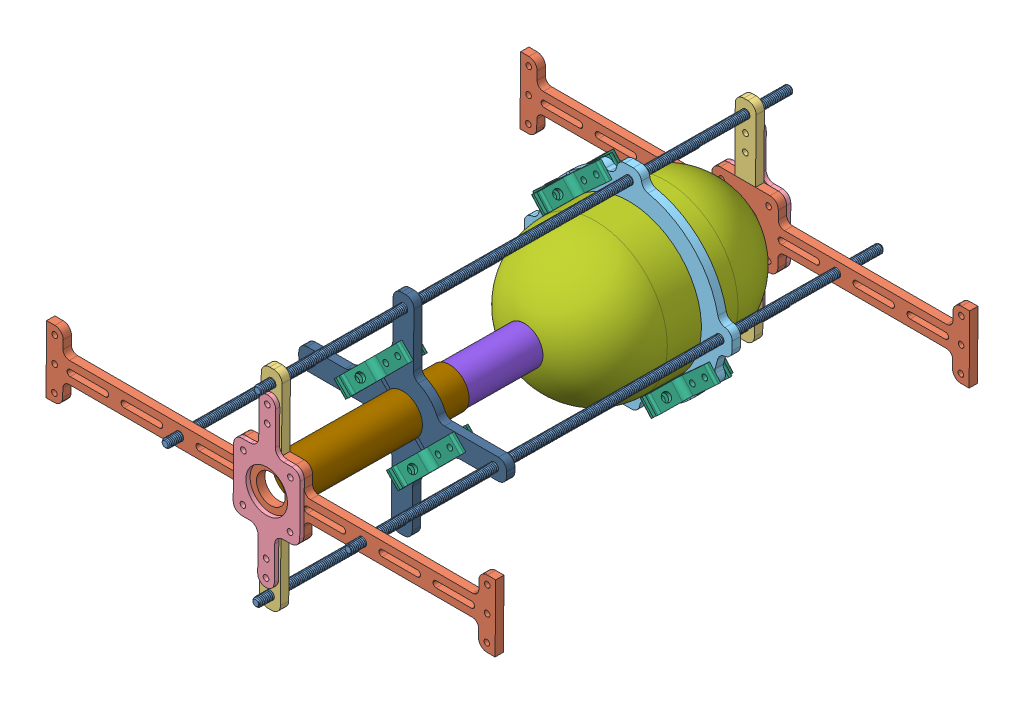
SolidWorks assembly FullCage, configuration Default. Lengths in mm.
Overall size (342.9 209.34 408.77).
42 component instances, 10 part files, 6 mates.
Components (placement in the parent):
- 98804A107_18-8 Stainless Steel Threaded Rod-1: 98804A107_18-8 Stainless Steel Threaded Rod [98804A107] at (0 -68.3672 170.2224) x (1 0 0) z (0 0.008727 0.999962) size (6.68 6.43 407.51)
- Cage Lid-1: Cage Lid [Default] x (1 0 0) z (0 -0.008727 -0.999962) size (342.9 158.75 9.53)
  - Bearing_CrossBarHeavy-1: Bearing_CrossBarHeavy [Default] at origin size (342.9 50.8 6.35)
  - CrossBar_Extension-1: CrossBar_Extension [Default] at (0 52.3875 0) x (0 -1 0) z (-1 0 0) size (53.98 6.35 15.88)
  - CrossBar_Extension-2: CrossBar_Extension [Default] at (0 -52.3875 0) x (0 1 0) z (1 0 0) size (53.98 6.35 15.88)
  - CageBracket-1: CageBracket [Default] at (0 0 9.525) x (0 1 0) z (-1 0 0) size (127 3.17 50.8)
- TankRing_Assy-1: TankRing_Assy [Default] at (0 0.7217 82.6939) x (0.73993 0.672659 -0.00587) z (0.672684 -0.739901 0.006457) size (180.05 57.15 180.38)
  - TankRing-1: TankRing [Default] x (0.73993 0 0.672684) z (-0.672684 0 0.73993) size (125.18 6.35 129.98)
  - TankRing_Bracket-1: TankRing_Bracket [8982K116] at (-17.4625 22.225 62.2074) size (31.75 25.4 12.7)
  - TankRing_Bracket-2: TankRing_Bracket [8982K116] at (-17.4625 22.225 -62.2074) size (31.75 25.4 12.7)
  - TankRing_Bracket-5: TankRing_Bracket [8982K116] at (-17.4625 -15.875 62.2074) x (1 0 0) z (0 0 -1) size (31.75 25.4 12.7)
  - TankRing_Bracket-6: TankRing_Bracket [8982K116] at (-17.4625 -15.875 -62.2074) x (1 0 0) z (0 0 -1) size (31.75 25.4 12.7)
- 98804A107_18-8 Stainless Steel Threaded Rod-2: 98804A107_18-8 Stainless Steel Threaded Rod [98804A107] at (-69.85 1.4802 169.6128) x (0 -0.999962 0.008727) z (0 0.008727 0.999962) size (6.68 6.43 407.51)
- 98804A107_18-8 Stainless Steel Threaded Rod-3: 98804A107_18-8 Stainless Steel Threaded Rod [98804A107] at (0 71.3275 169.0033) x (-1 0 0) z (0 0.008727 0.999962) size (6.68 6.43 407.51)
- 98804A107_18-8 Stainless Steel Threaded Rod-4: 98804A107_18-8 Stainless Steel Threaded Rod [98804A107] at (69.85 1.4802 169.6128) x (0 0.999962 -0.008727) z (0 0.008727 0.999962) size (6.68 6.43 407.51)
- TankRing_Assy-4: TankRing_Assy [Default] at (0 0.7217 82.6939) x (-0.73993 -0.672659 0.00587) z (-0.672684 0.739901 -0.006457) size (180.05 57.15 180.38)
  - TankRing-1: TankRing [Default] x (0.73993 0 0.672684) z (-0.672684 0 0.73993) size (125.18 6.35 129.98)
  - TankRing_Bracket-1: TankRing_Bracket [8982K116] at (-17.4625 22.225 62.2074) size (31.75 25.4 12.7)
  - TankRing_Bracket-2: TankRing_Bracket [8982K116] at (-17.4625 22.225 -62.2074) size (31.75 25.4 12.7)
  - TankRing_Bracket-5: TankRing_Bracket [8982K116] at (-17.4625 -15.875 62.2074) x (1 0 0) z (0 0 -1) size (31.75 25.4 12.7)
  - TankRing_Bracket-6: TankRing_Bracket [8982K116] at (-17.4625 -15.875 -62.2074) x (1 0 0) z (0 0 -1) size (31.75 25.4 12.7)
- Cage Lid-2: Cage Lid [Default] at (0 3.1032 355.5865) x (1 0 0) z (0 0.008727 0.999962) size (342.9 158.75 9.53)
  - Bearing_CrossBarHeavy-1: Bearing_CrossBarHeavy [Default] at origin size (342.9 50.8 6.35)
  - CrossBar_Extension-1: CrossBar_Extension [Default] at (0 52.3875 0) x (0 -1 0) z (-1 0 0) size (53.98 6.35 15.88)
  - CrossBar_Extension-2: CrossBar_Extension [Default] at (0 -52.3875 0) x (0 1 0) z (1 0 0) size (53.98 6.35 15.88)
  - CageBracket-1: CageBracket [Default] at (0 0 9.525) x (0 1 0) z (-1 0 0) size (127 3.17 50.8)
- LoFi Tank+Reg-1: LoFi Tank+Reg [Default] at (0 0.7659 87.769) x (-0.921374 -0.388662 0.003392) z (0 -0.008727 -0.999962) size (111.12 111.12 340.27)
  - LoFi Tank-1: LoFi Tank [Default] at origin size (111.12 111.12 163.23)
  - LoFi Reg 1-1: LoFi Reg 1 [Default] at (0 0 -80.6816) x (-0.38598 0.922507 0) z (-0.922507 -0.38598 0) size (28.57 57.15 28.57)
  - LoFi Reg 2-1: LoFi Reg 2 [Default] at (0 0 -137.8316) x (-0.99247 0.12249 0) z (-0.12249 -0.99247 0) size (30.16 119.89 30.16)
- RegRing_Assy-1: RegRing_Assy [Default] at (0 2.28 261.2578) x (0.707107 0.70708 -0.006171) z (-0.707107 0.70708 -0.006171) size (145.48 57.15 145.48)
  - RegRing-1: RegRing [Default] x (0.707107 0 -0.707107) z (0.707107 0 0.707107) size (102.87 6.35 102.87)
  - TankRing_Bracket-1: TankRing_Bracket [8982K116] at (-17.4625 22.225 28.4622) size (31.75 25.4 12.7)
  - TankRing_Bracket-2: TankRing_Bracket [8982K116] at (-17.4625 -15.875 28.4622) x (1 0 0) z (0 0 -1) size (31.75 25.4 12.7)
  - TankRing_Bracket-3: TankRing_Bracket [8982K116] at (-17.4625 22.225 -28.4622) size (31.75 25.4 12.7)
  - TankRing_Bracket-4: TankRing_Bracket [8982K116] at (-17.4625 -15.875 -28.4622) x (1 0 0) z (0 0 -1) size (31.75 25.4 12.7)
- RegRing_Assy-2: RegRing_Assy [Default] at (0 2.28 261.2578) x (-0.707107 -0.70708 0.006171) z (0.707107 -0.70708 0.006171) size (145.48 57.15 145.48)
  - RegRing-1: RegRing [Default] x (0.707107 0 -0.707107) z (0.707107 0 0.707107) size (102.87 6.35 102.87)
  - TankRing_Bracket-1: TankRing_Bracket [8982K116] at (-17.4625 22.225 28.4622) size (31.75 25.4 12.7)
  - TankRing_Bracket-2: TankRing_Bracket [8982K116] at (-17.4625 -15.875 28.4622) x (1 0 0) z (0 0 -1) size (31.75 25.4 12.7)
  - TankRing_Bracket-3: TankRing_Bracket [8982K116] at (-17.4625 22.225 -28.4622) size (31.75 25.4 12.7)
  - TankRing_Bracket-4: TankRing_Bracket [8982K116] at (-17.4625 -15.875 -28.4622) x (1 0 0) z (0 0 -1) size (31.75 25.4 12.7)
Mates (geometry in assembly coordinates):
- Coincident1: coincident aligned: line of 98804A107_18-8 Stainless Steel Threaded Rod-1 through (0 -66.595 373.287) axis (0 -0.008727 -0.999962); line of Cage Lid-1/CrossBar_Extension-1 through (0 -69.8473 0.6095) axis (0 -0.008727 -0.999962)
- Coincident2: coincident anti-aligned: line of 98804A107_18-8 Stainless Steel Threaded Rod-1 through (0 -66.595 373.287) axis (0 -0.008727 -0.999962); line of TankRing_Assy-1/TankRing-1 through (0 -69.1257 83.3035) axis (0 0.008727 0.999962)
- Coincident5: coincident anti-aligned: line of TankRing_Assy-1/TankRing-1 through (-69.85 0.7217 82.6939) axis (0 0.008727 0.999962); line of 98804A107_18-8 Stainless Steel Threaded Rod-2 through (-69.85 3.2523 372.6775) axis (0 -0.008727 -0.999962)
- Concentric1: concentric anti-aligned: cylinder of TankRing_Assy-4/TankRing-1 through (0 0.7771 89.0437) axis (0 -0.008727 -0.999962) radius 55.88; cylinder of LoFi Tank+Reg-1/LoFi Tank-1 through (0 1.47 168.4476) axis (0 0.008727 0.999962) radius 55.5625
- Coincident6: coincident aligned: line of 98804A107_18-8 Stainless Steel Threaded Rod-1 through (0 -66.595 373.287) axis (0 -0.008727 -0.999962); line of RegRing_Assy-1/RegRing-1 through (0 -67.5674 261.8674) axis (0 -0.008727 -0.999962)
- Coincident7: coincident aligned: line of 98804A107_18-8 Stainless Steel Threaded Rod-2 through (-69.85 3.2523 372.6775) axis (0 -0.008727 -0.999962); line of RegRing_Assy-1/RegRing-1 through (-69.85 2.28 261.2578) axis (0 -0.008727 -0.999962)
